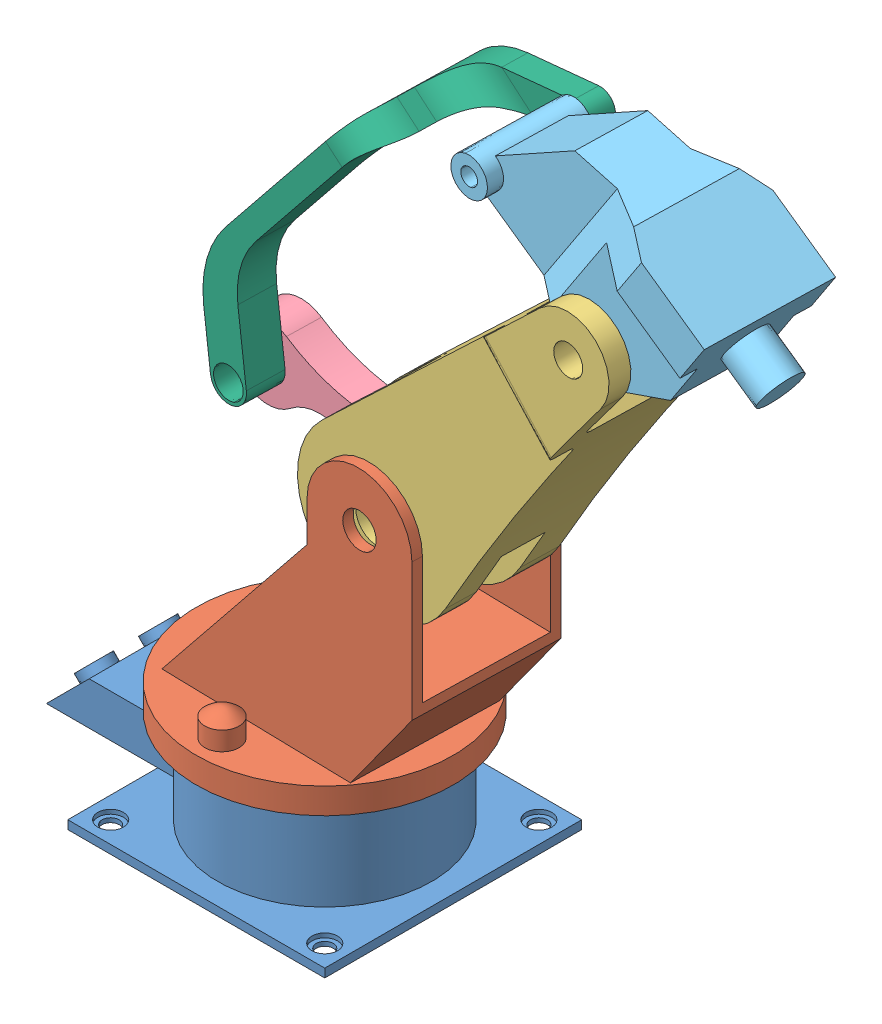
SolidWorks assembly Assem, configuration 默认. Lengths in mm.
Overall size (829.78 951.89 307.83).
6 component instances, 6 part files, 12 mates.
Components (placement in the parent):
- Base-1: Base [默认] at (43.6508 -26.9312 400) size (400 120 300)
- RotPlat-1: RotPlat [默认] at (43.6508 93.0688 400) x (-0.999735 0 -0.023042) z (0.023042 0 -0.999735) size (343.2 353.56 300)
- Arm_L-1: Arm_L [默认] at (174.1016 383.93 403.4499) x (0.688545 -0.72502 0.01587) z (-0.023042 0 0.999735) size (189.22 553.41 200)
- Connector1-1: Connector1 [默认] at (143.1893 381.6362 382.3992) x (-0.997076 -0.072883 -0.022981) z (-0.023042 0 0.999735) size (277.71 164.3 40)
- Connector2-1: Connector2 [默认] at (385.1104 693.6776 412.2047) x (-0.833451 0.55226 -0.019209) z (0.023042 0 -0.999735) size (327.98 172.5 150)
- ConnectRod-1: ConnectRod [默认] at (194.1835 753.2873 392.8003) x (-0.777131 0.629084 -0.017911) z (0.023042 0 -0.999735) size (122.1 496.61 150)
Mates (geometry in assembly coordinates):
- 同心1: concentric aligned: cylinder of Base-1 through (43.6508 83.0688 400) axis (0 -1 0) radius 125; cylinder of RotPlat-1 through (43.6508 123.0688 400) axis (0 -1 0) radius 150
- 重合1: coincident anti-aligned: plane of Base-1 through (43.6508 93.0688 400) normal (0 1 0); plane of RotPlat-1 through (43.6508 93.0688 400) normal (0 -1 0)
- 同心2: concentric anti-aligned: cylinder of RotPlat-1 through (176.0704 383.93 318.0294) axis (-0.023042 0 0.999735) radius 62.7; cylinder of Arm_L-1 through (171.7974 383.93 503.4234) axis (0.023042 0 -0.999735) radius 94.6123
- 平行1: parallel anti-aligned: plane of RotPlat-1 through (-107.9914 470.4814 469.5243) normal (0.023042 0 -0.999735); plane of Arm_L-1 through (545.6045 441.2752 477.0296) normal (-0.023042 0 0.999735)
- 距离1: distance = 7.5568 mm anti-aligned: plane of Arm_L-1 through (545.6045 441.2752 477.0296) normal (-0.023042 0 0.999735); plane of RotPlat-1 through (-107.9914 470.4814 469.5243) normal (0.023042 0 -0.999735)
- 同心3: concentric aligned: cylinder of Arm_L-1 through (171.7974 383.93 503.4234) axis (0.023042 0 -0.999735) radius 25; cylinder of Connector1-1 through (173.6484 383.93 423.1119) axis (0.023042 0 -0.999735) radius 20
- 同心4: concentric aligned: cylinder of Arm_L-1 through (437.4329 699.5232 509.5457) axis (0.023042 0 -0.999735) radius 17.35; cylinder of Connector2-1 through (437.9193 699.5232 488.4418) axis (0.023042 0 -0.999735) radius 15
- 同心5: concentric anti-aligned: cylinder of Connector2-1 through (280.2261 787.3076 549.8245) axis (0.023042 0 -0.999735) radius 10; cylinder of ConnectRod-1 through (285.5258 787.3076 319.8856) axis (-0.023042 0 0.999735) radius 11.8
- 重合7: coincident anti-aligned: plane of Connector2-1 through (284.8345 787.3076 349.8776) normal (0.023042 0 -0.999735); plane of ConnectRod-1 through (825.418 1421.4036 362.337) normal (-0.023042 0 0.999735)
- 重合8: coincident anti-aligned: plane of Arm_L-1 through (383.7597 285.6228 387.9439) normal (-0.023042 0 0.999735); plane of Connector1-1 through (28.3736 392.483 379.753) normal (0.023042 0 -0.999735)
- 重合10: coincident anti-aligned: plane of Connector1-1 through (27.452 392.483 419.7424) normal (-0.023042 0 0.999735); plane of ConnectRod-1 through (212.6159 666.1429 424.01) normal (0.023042 0 -0.999735)
- 同心6: concentric anti-aligned: cylinder of Connector1-1 through (-4.5886 431.9618 419.0039) axis (0.023042 0 -0.999735) radius 15; cylinder of ConnectRod-1 through (-2.1514 431.9618 313.2552) axis (-0.023042 0 0.999735) radius 17.8
